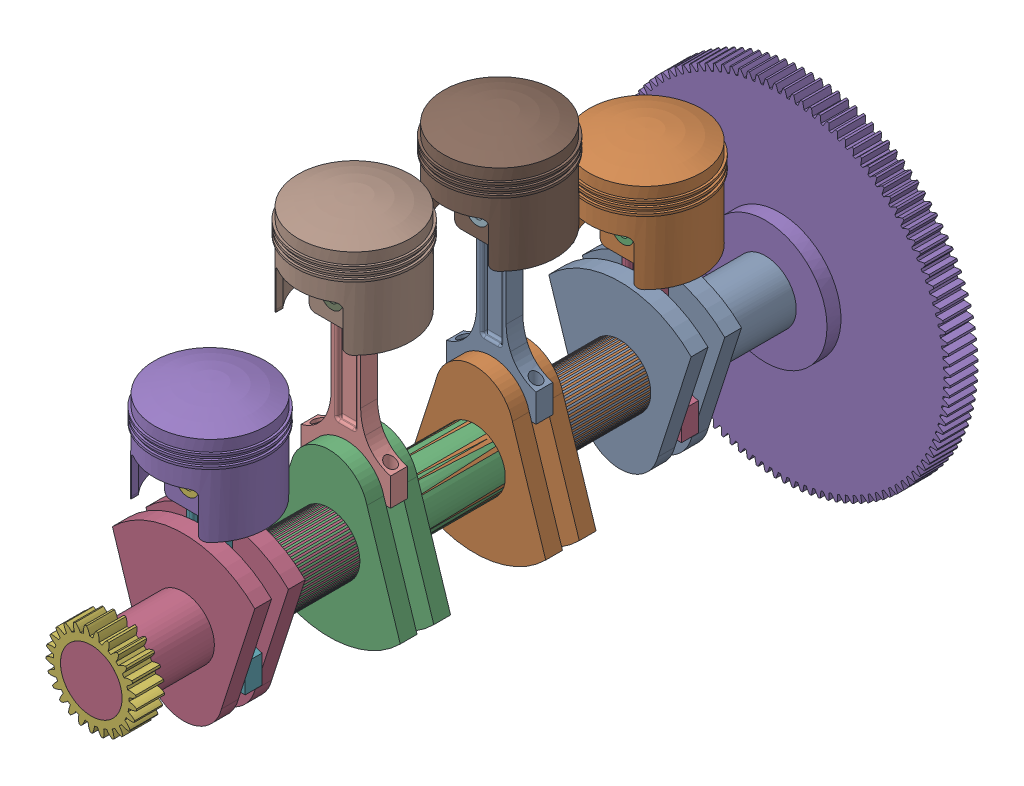
SolidWorks assembly sub_int_main, configuration Default. Lengths in mm.
Overall size (304.94 412.07 652.5).
23 component instances, 7 part files, 12 mates.
Components (placement in the parent):
- crankshaft-1: crankshaft [Default] at (-2.7673 -15.1795 168.2807) size (127.28 145 652.5)
- piston_sys-1: piston_sys [Default] at (-38.9621 84.9434 72.3533) x (0.999982 -0.006033 0) z (0 0 1) size (104 220.01 104)
  - piston-1: piston [Default] at (36.9808 2.9936 88.4626) size (104 90 104)
  - wrist_pin-1: wrist_pin [Default] at (36.9808 22.9936 108.4626) x (-0.988472 -0.151404 0) z (0 0 1) size (20 20 40)
  - connecting_rod-1: connecting_rod [Default] at (36.9808 22.9936 88.4275) x (1 -0.000128 0) z (0 0 1) size (80 170 15)
  - piston_cap-2: piston_cap [Default] at (36.9617 -127.0064 80.9275) x (1 -0.000128 0) z (0 0 1) (suppressed, hidden)
- piston_sys-2: piston_sys [Default] at (-39.729 163.9309 -57.6467) size (104 220.01 104)
  - piston-1: piston [Default] at (36.9808 2.9936 88.4626) size (104 90 104)
  - wrist_pin-1: wrist_pin [Default] at (36.9808 22.9936 108.4626) x (-0.988472 -0.151404 0) z (0 0 1) size (20 20 40)
  - connecting_rod-1: connecting_rod [Default] at (36.9808 22.9936 88.4275) x (1 -0.000128 0) z (0 0 1) size (80 170 15)
  - piston_cap-2: piston_cap [Default] at (36.9617 -127.0064 80.9275) x (1 -0.000128 0) z (0 0 1) (suppressed, hidden)
- piston_sys-3: piston_sys [Default] at (-39.729 163.9309 -187.6467) size (104 220.01 104)
  - piston-1: piston [Default] at (36.9808 2.9936 88.4626) size (104 90 104)
  - wrist_pin-1: wrist_pin [Default] at (36.9808 22.9936 108.4626) x (-0.988472 -0.151404 0) z (0 0 1) size (20 20 40)
  - connecting_rod-1: connecting_rod [Default] at (36.9808 22.9936 88.4275) x (1 -0.000128 0) z (0 0 1) size (80 170 15)
  - piston_cap-2: piston_cap [Default] at (36.9617 -127.0064 80.9275) x (1 -0.000128 0) z (0 0 1) (suppressed, hidden)
- piston_sys-4: piston_sys [Default] at (-39.729 84.7228 -317.6467) size (104 220.01 104)
  - piston-1: piston [Default] at (36.9808 2.9936 88.4626) size (104 90 104)
  - wrist_pin-1: wrist_pin [Default] at (36.9808 22.9936 108.4626) x (-0.988472 -0.151404 0) z (0 0 1) size (20 20 40)
  - connecting_rod-1: connecting_rod [Default] at (36.9808 22.9936 88.4275) x (1 -0.000128 0) z (0 0 1) size (80 170 15)
  - piston_cap-2: piston_cap [Default] at (36.9617 -127.0064 80.9275) x (1 -0.000128 0) z (0 0 1) (suppressed, hidden)
- flywheel-1: flywheel [Default] at (11.7553 0.6518 -375.2695) x (0 0 1) z (-1 0 0) size (50 304.94 304.94)
- crankshaft_sprocket-1: crankshaft_sprocket [Default] at (-21.348 14.7399 253.2807) x (0 0 -1) z (1 0 0) size (25 80.78 80.93)
Mates (geometry in assembly coordinates):
- Concentric1: concentric anti-aligned: cylinder of crankshaft-1 through (-2.7673 -42.2836 153.2807) axis (0 0 1) radius 25; cylinder of piston_sys-1/piston_cap-2 through (-2.7673 -42.2836 168.2807) axis (0 0 -1) radius 25
- Concentric2: concentric aligned: cylinder of crankshaft-1 through (-2.7673 36.9246 38.2807) axis (0 0 -1) radius 25; cylinder of piston_sys-2/piston_cap-2 through (-2.7673 36.9246 38.2807) axis (0 0 -1) radius 25
- Coincident1: coincident anti-aligned: plane of crankshaft-1 through (-2.7673 34.8205 38.2807) normal (0 0 -1); plane of piston_sys-2/connecting_rod-1 through (-65.9879 100.9805 38.2807) normal (0 0 1)
- Coincident2: coincident anti-aligned: plane of crankshaft-1 through (-2.7673 -40.1795 168.2807) normal (0 0 -1); plane of piston_sys-1/piston_cap-2 through (-2.7673 -42.2836 168.2807) normal (0 0 1)
- Concentric3: concentric anti-aligned: cylinder of crankshaft-1 through (-2.7673 36.9246 -106.7193) axis (0 0 1) radius 25; cylinder of piston_sys-3/piston_cap-2 through (-2.7673 36.9246 -91.7193) axis (0 0 -1) radius 25
- Coincident3: coincident anti-aligned: plane of crankshaft-1 through (-2.7673 34.8205 -91.7193) normal (0 0 -1); plane of piston_sys-3/connecting_rod-1 through (-65.9879 100.9805 -91.7193) normal (0 0 1)
- Concentric4: concentric aligned: cylinder of crankshaft-1 through (-2.7673 -42.2836 -221.7193) axis (0 0 -1) radius 25; cylinder of piston_sys-4/piston_cap-2 through (-2.7673 -42.2836 -221.7193) axis (0 0 -1) radius 25
- Coincident4: coincident anti-aligned: plane of crankshaft-1 through (-2.7673 -40.1795 -221.7193) normal (0 0 -1); plane of piston_sys-4/piston_cap-2 through (-2.7673 -42.2836 -221.7193) normal (0 0 1)
- Concentric5: concentric anti-aligned: cylinder of crankshaft-1 through (-2.7673 -2.6795 -336.7193) axis (0 0 1) radius 27.5; cylinder of flywheel-1 through (-2.7673 -2.6795 -324.2192) axis (0 0 -1) radius 27.5
- Coincident5: coincident anti-aligned: circle of crankshaft-1; circle of flywheel-1
- Concentric6: concentric anti-aligned: cylinder of crankshaft-1 through (-2.7673 -2.6795 268.2807) axis (0 0 -1) radius 27.5; cylinder of crankshaft_sprocket-1 through (-2.7673 -2.6795 215.7807) axis (0 0 1) radius 27.5
- Coincident6: coincident aligned: circle of crankshaft-1; circle of crankshaft_sprocket-1
